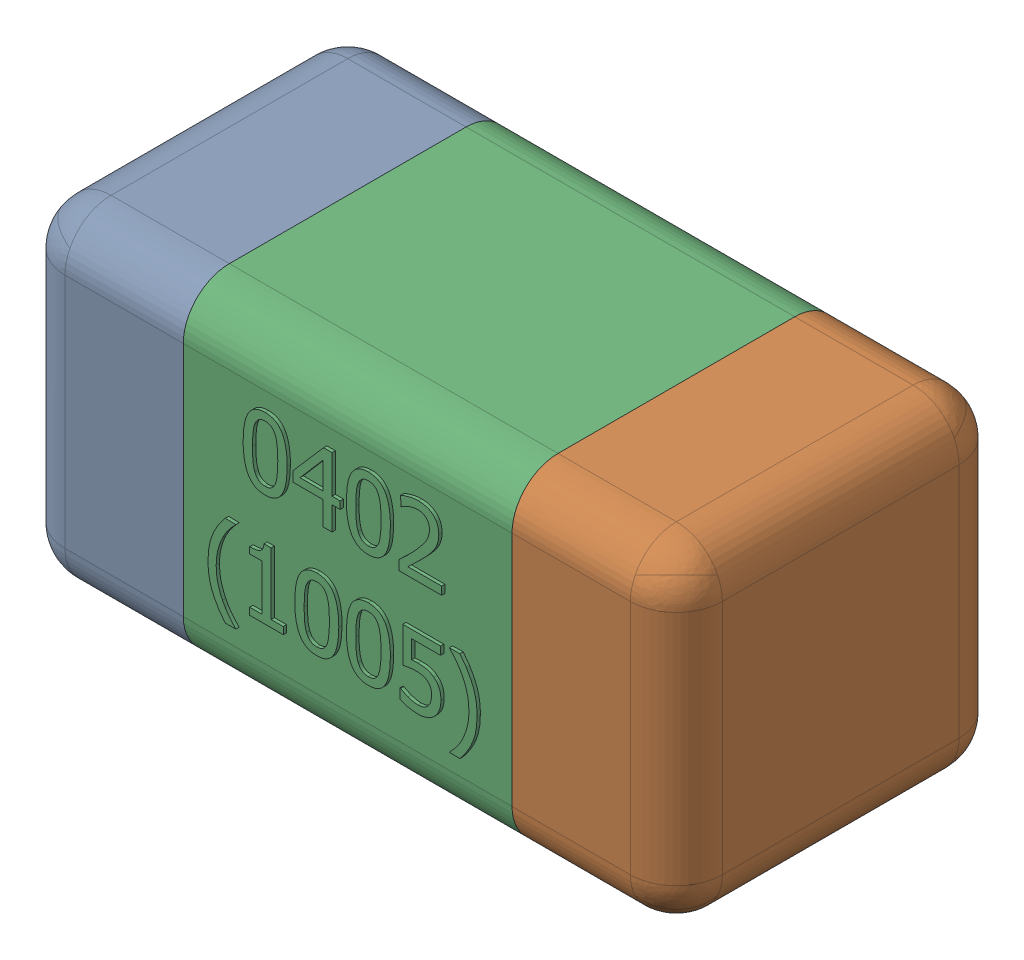
SolidWorks assembly C29, configuration Standard. Lengths in mm.
Overall size (1.01 0.51 0.51).
4 component instances, 3 part files, 0 mates.
Components (placement in the parent):
- C29-subassembly-1-1: C29-subassembly-1 [Standard] at (-14.8999 -16.8 0) x (1 0 0) z (0 0 1) size (1.01 0.51 0.51)
  - User Library-0402_Cap-1: User Library-0402_Cap [Standard] at origin size (0.26 0.51 0.51)
  - User Library-0402_Cap-1-1: User Library-0402_Cap-1 [Standard] at origin size (0.26 0.5 0.51)
  - User Library-0402_Cap-2-1: User Library-0402_Cap-2 [Standard] at origin size (0.5 0.5 0.51)
